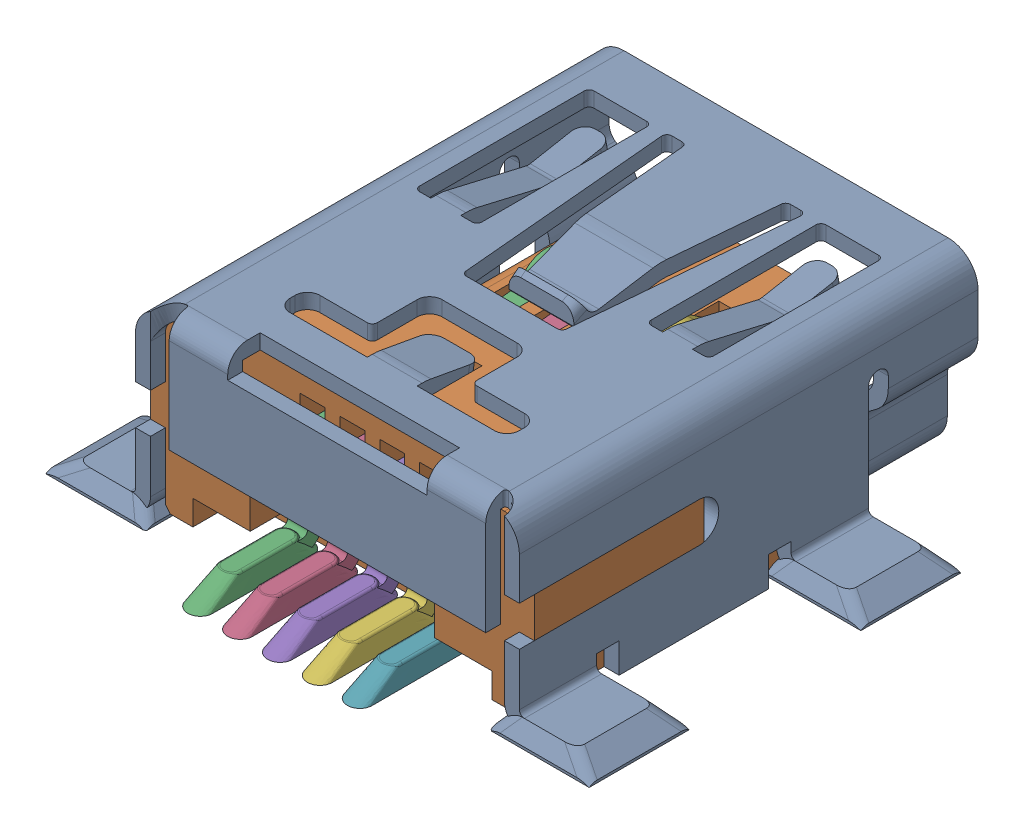
SolidWorks assembly MINIUSB - MEASURED, configuration Predeterminado. Lengths in mm.
Overall size (11.03 4.95 10.42).
7 component instances, 3 part files, 0 mates.
Components (placement in the parent):
- MINIUSBSHELL-1: MINIUSBSHELL [Predeterminado] at origin size (11.03 3.97 9.48)
- MINIUSBCORE-1: MINIUSBCORE [Predeterminado] at (0 0 6.7) x (-1 0 0) z (0 0 -1) size (7.7 4.5 8.2)
- MINI USB CONTACT-1: MINI USB CONTACT [Predeterminado] at (-1.6 0 5.7) x (-1 0 0) z (0 0 -1) size (0.53 2.55 9.41)
- MINI USB CONTACT-2: MINI USB CONTACT [Predeterminado] at (-0.8 0 5.7) x (-1 0 0) z (0 0 -1) size (0.53 2.55 9.41)
- MINI USB CONTACT-3: MINI USB CONTACT [Predeterminado] at (0 0 5.7) x (-1 0 0) z (0 0 -1) size (0.53 2.55 9.41)
- MINI USB CONTACT-4: MINI USB CONTACT [Predeterminado] at (0.8 0 5.7) x (-1 0 0) z (0 0 -1) size (0.53 2.55 9.41)
- MINI USB CONTACT-5: MINI USB CONTACT [Predeterminado] at (1.6 0 5.7) x (-1 0 0) z (0 0 -1) size (0.53 2.55 9.41)
